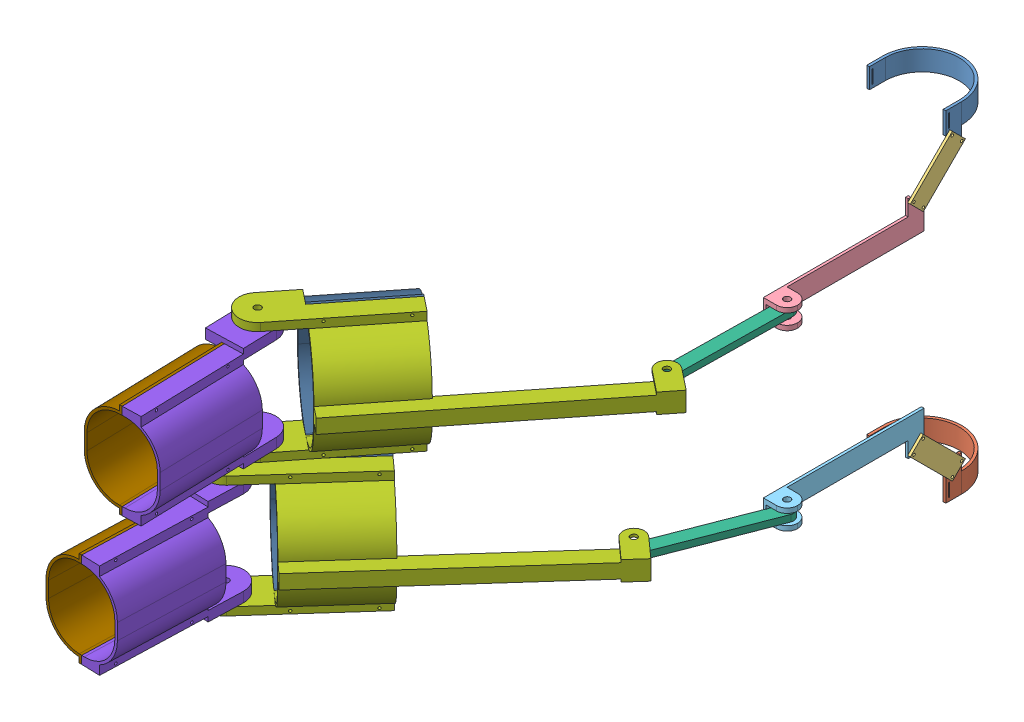
SolidWorks assembly Assem1, configuration Default. Lengths in mm.
Overall size (862.71 645.29 1368.86).
18 component instances, 10 part files, 22 mates.
Components (placement in the parent):
- LeftShoulder-1: LeftShoulder [Default] at (5.5981 85.1964 156.7778) size (150 68.1 105)
- RightShoulder2-2: RightShoulder2 [Default] at (5.5981 -483.8927 156.7778) x (-1 0 0) z (0 0 1) size (150 68.1 105)
- Flex-1: Flex [Default] at (80.5981 88.3784 179.3532) x (0 -0.707107 0.707107) z (1 0 0) size (113 35 5)
- Flex-2: Flex [Default] at (80.5981 -462.326 154.6045) x (0 0.707107 0.707107) z (1 0 0) size (113 35 5)
- LeftSupport-1: LeftSupport [Default] at (75.5981 -15.5663 528.1436) x (0 -1 0) z (1 0 0) size (68.1 300 45)
- RightSupport-1: RightSupport [Default] at (80.5981 -383.13 528.1436) x (0 1 0) z (-1 0 0) size (68.1 300 45)
- PistonSim-1: PistonSim [Default] at (26.6576 -374.13 734.1863) x (0.360423 0 -0.932789) z (0 1 0) size (250 25 12.5)
- PistonSim-2: PistonSim [Default] at (84.7059 -24.5663 745.4407) x (0.014288 0 -0.999898) z (0 -1 0) size (250 25 12.5)
- AsmLeg-1: AsmLeg [Default] at (-248.8468 -138.7501 1463.5606) x (0 -1 0) z (0.666648 0 -0.745372) size (230 319.02 812.95)
  - SupDownPart-1: SupDownPart [Default] at (121.8799 276.9922 254.5995) size (230 157 600)
  - InfDownPart-1: InfDownPart [Default] at (147.8799 146.8003 28.4612) x (1 0 0) z (0 0.643074 0.765804) size (198 105 300)
  - InfSupPart-1: InfSupPart [Default] at (297.8799 246.3548 -55.1384) x (-1 0 0) z (0 0.643074 0.765804) size (180 70 200)
  - SupUpPart-1: SupUpPart [Default] at (121.8799 456.9922 414.5995) x (1 0 0) z (0 0 -1) size (230 95 160)
- AsmLeg-2: AsmLeg [Default] at (-125.304 183.8136 1493.5489) x (0 -1 0) z (0.620264 0 -0.784393) size (230 319.02 812.95)
  - SupDownPart-1: SupDownPart [Default] at (121.8799 276.9922 254.5995) size (230 157 600)
  - InfDownPart-1: InfDownPart [Default] at (147.8799 146.8003 28.4612) x (1 0 0) z (0 0.643074 0.765804) size (198 105 300)
  - InfSupPart-1: InfSupPart [Default] at (297.8799 246.3548 -55.1384) x (-1 0 0) z (0 0.643074 0.765804) size (180 70 200)
  - SupUpPart-1: SupUpPart [Default] at (121.8799 456.9922 414.5995) x (1 0 0) z (0 0 -1) size (230 95 160)
Mates (geometry in assembly coordinates):
- Coincident1: coincident anti-aligned: plane of LeftShoulder-1 through (80.5981 123.2964 156.7778) normal (1 0 0); plane of Flex-1 through (80.5981 88.3784 179.3532) normal (-1 0 0)
- Concentric2: concentric aligned: circle of LeftShoulder-1; circle of Flex-1
- Concentric3: concentric aligned: circle of LeftShoulder-1; circle of Flex-1
- Coincident6: coincident aligned: plane of LeftShoulder-1 through (80.5981 123.2964 156.7778) normal (1 0 0); plane of RightShoulder2-2 through (80.5981 -521.9927 156.7778) normal (1 0 0)
- Coincident7: coincident aligned: plane of LeftShoulder-1 through (5.5981 123.2964 186.7778) normal (0 0 1); plane of RightShoulder2-2 through (5.5981 -521.9927 186.7778) normal (0 0 1)
- Coincident8: coincident anti-aligned: plane of RightShoulder2-2 through (80.5981 -521.9927 156.7778) normal (1 0 0); plane of Flex-2 through (80.5981 -462.326 154.6045) normal (-1 0 0)
- Concentric5: concentric aligned: cylinder of RightShoulder2-2 through (80.5981 -480.0036 179.3532) axis (-1 0 0) radius 2.3813; cylinder of Flex-2 through (85.5981 -480.0036 179.3532) axis (-1 0 0) radius 2.3813
- Concentric6: concentric aligned: cylinder of RightShoulder2-2 through (80.5981 -462.326 161.6755) axis (-1 0 0) radius 2.3813; cylinder of Flex-2 through (85.5981 -462.326 161.6755) axis (-1 0 0) radius 2.3813
- Coincident13: coincident anti-aligned: plane of Flex-1 through (80.5981 88.3784 179.3532) normal (-1 0 0); plane of LeftSupport-1 through (80.5981 -15.5663 528.1436) normal (1 0 0)
- Concentric7: concentric anti-aligned: circle of Flex-1; cylinder of LeftSupport-1 through (80.5981 8.4753 252.1852) axis (-1 0 0) radius 2.3813
- Concentric8: concentric aligned: cylinder of Flex-1 through (85.5981 -9.2024 234.5075) axis (-1 0 0) radius 2.3813; cylinder of LeftSupport-1 through (80.5981 -9.2024 234.5075) axis (-1 0 0) radius 2.3813
- Coincident16: coincident anti-aligned: plane of Flex-2 through (80.5981 -462.326 154.6045) normal (-1 0 0); plane of RightSupport-1 through (80.5981 -383.13 528.1436) normal (1 0 0)
- Concentric9: concentric anti-aligned: circle of Flex-2; circle of RightSupport-1
- Concentric10: concentric anti-aligned: circle of Flex-2; circle of RightSupport-1
- Concentric11: concentric anti-aligned: circle of RightSupport-1; circle of PistonSim-1
- Coincident25: coincident anti-aligned: plane of RightSupport-1 through (120.5981 -374.13 528.1436) normal (0 1 0); plane of PistonSim-1 through (26.6576 -374.13 734.1863) normal (0 -1 0)
- Concentric12: concentric anti-aligned: circle of LeftSupport-1; circle of PistonSim-2
- Coincident27: coincident anti-aligned: plane of LeftSupport-1 through (120.5981 -24.5663 528.1436) normal (0 -1 0); plane of PistonSim-2 through (84.7059 -24.5663 745.4407) normal (0 1 0)
- Concentric13: concentric anti-aligned: circle of PistonSim-1; circle of AsmLeg-1/SupDownPart-1
- Coincident29: coincident anti-aligned: plane of PistonSim-1 through (26.6576 -374.13 734.1863) normal (0 -1 0); plane of AsmLeg-1/SupDownPart-1 through (-285.5808 -374.13 1089.1328) normal (0 1 0)
- Concentric14: concentric anti-aligned: circle of PistonSim-2; circle of AsmLeg-2/SupDownPart-1
- Coincident31: coincident anti-aligned: plane of PistonSim-2 through (84.7059 -24.5663 745.4407) normal (0 1 0); plane of AsmLeg-2/SupDownPart-1 through (-184.6557 -24.5663 1122.0345) normal (0 -1 0)
